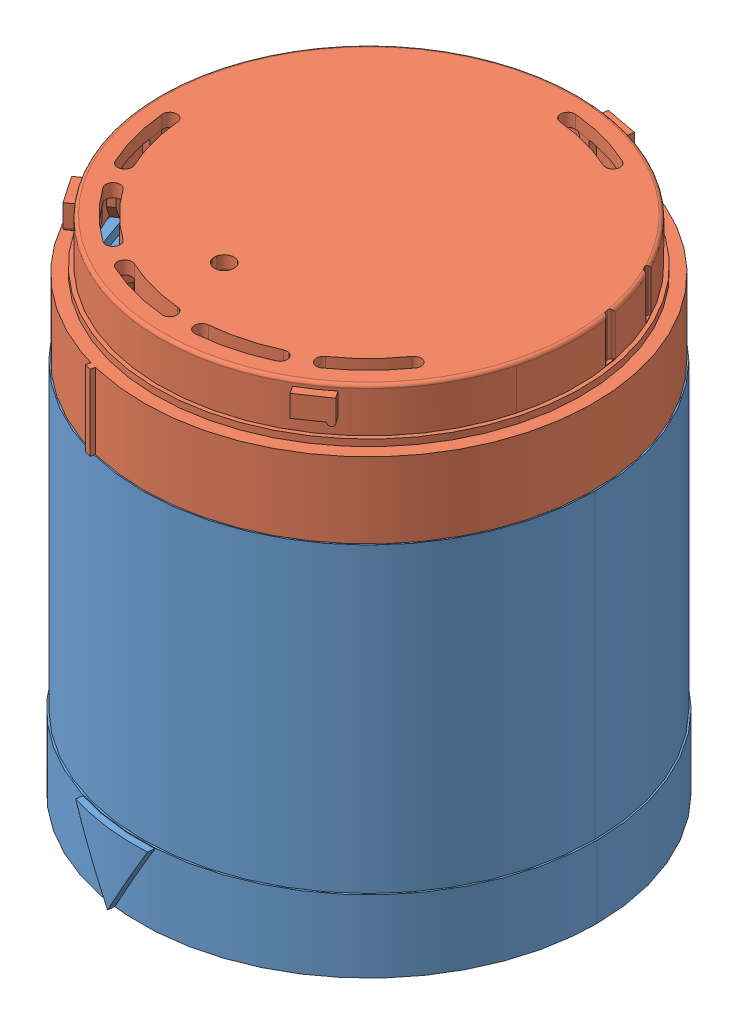
SolidWorks assembly 855t_module, configuration Red. Lengths in mm.
Overall size (84.2 76.26 84.69).
3 component instances, 2 part files, 0 mates.
Components (placement in the parent):
- 855t_module(2)^855t_module-1: 855t_module(2)^855t_module [Red] at origin size (84.2 76.26 84.69) (virtual)
  - 40378-011^855t_module(2)_855t_module-1: 40378-011^855t_module(2)_855t_module [default red] at origin size (69.5 65.01 72.38) (virtual)
  - 40378-007^855t_module(2)_855t_module-1: 40378-007^855t_module(2)_855t_module [Default] at (0 57 0) x (0.965926 0 0.258819) z (-0.258819 0 0.965926) (virtual)
